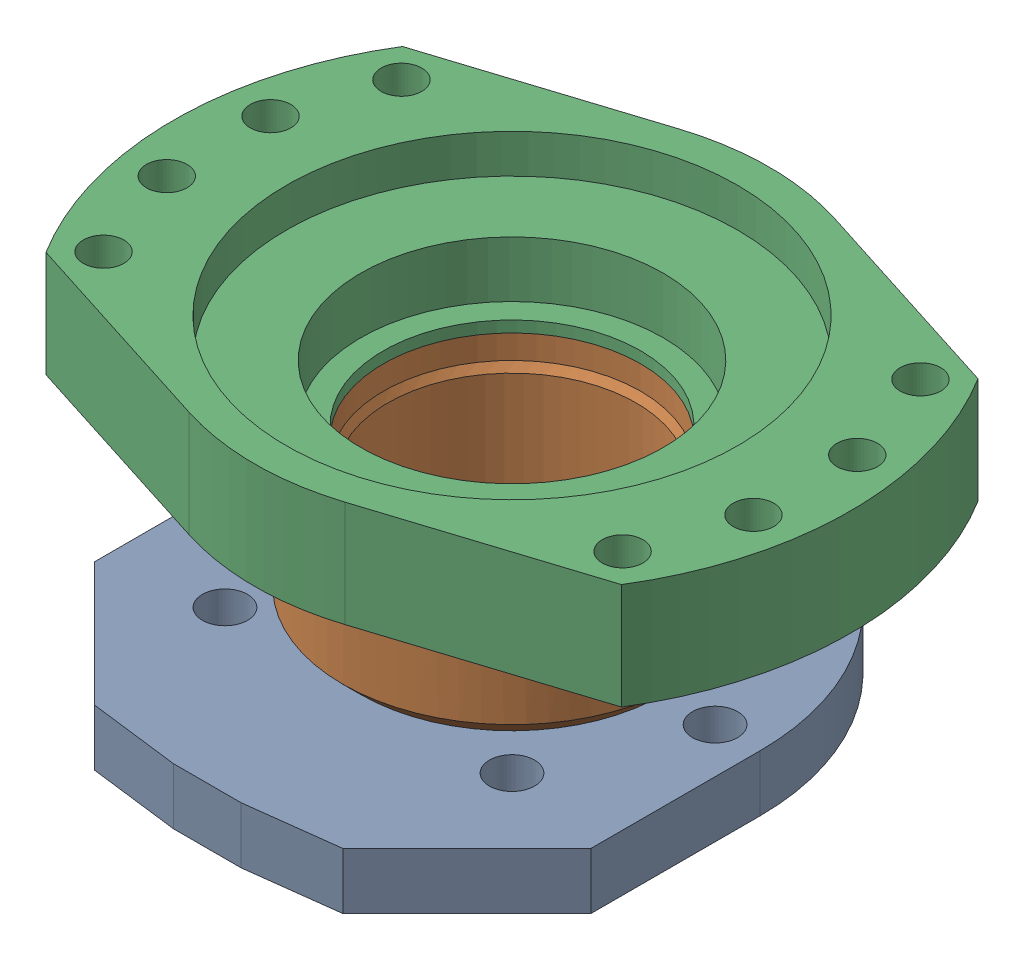
SolidWorks assembly g1_3_1_1_1_1_1, configuration 默认. Lengths in mm.
Overall size (300 154 249).
3 component instances, 3 part files, 0 mates.
Components (placement in the parent):
- g1_3_1_1_1_1-1_af0_1-1: g1_3_1_1_1_1-1_af0_1 [默认] at origin size (220 42 245)
- g1_3_1_1_1_1-2_af0_1-1: g1_3_1_1_1_1-2_af0_1 [默认] at (0 50 0) size (150 65 150)
- g1_3_1_1_1_1-3_af0_1-1: g1_3_1_1_1_1-3_af0_1 [默认] at (0 140 0) size (300 47 228)
